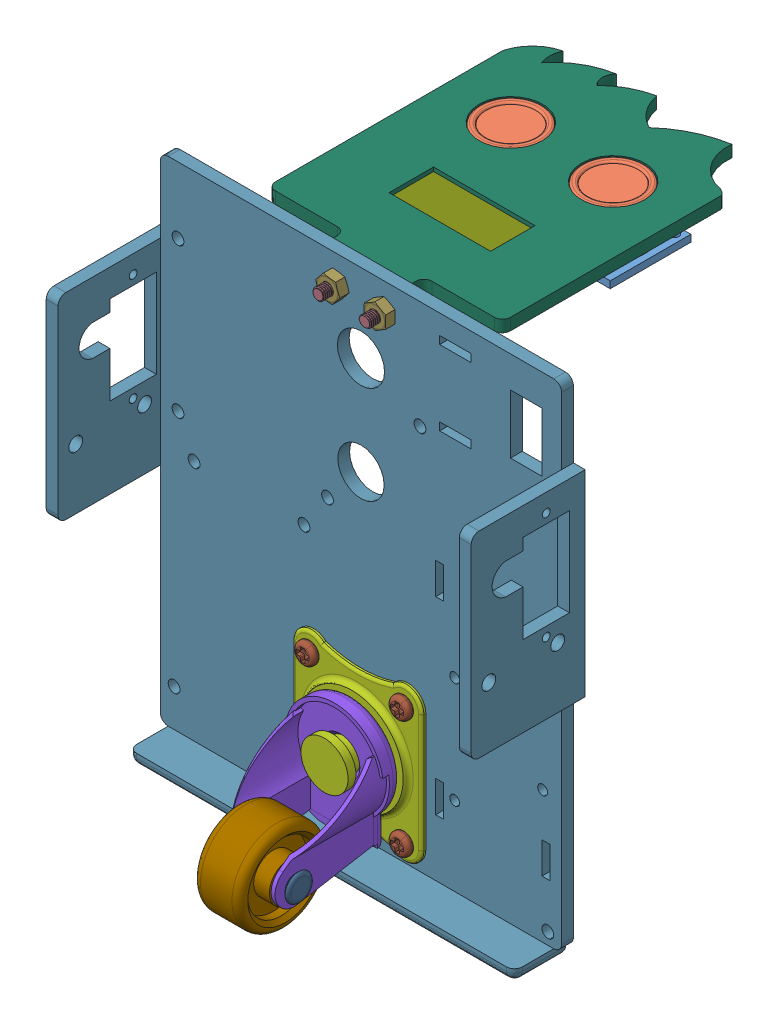
SolidWorks assembly DYOR_3D_OL, configuration Predeterminado. Lengths in mm.
Overall size (108 131.39 112.97).
53 component instances, 19 part files, 17 mates.
Components (placement in the parent):
- HC-SR04 Ping Sensor-1: HC-SR04 Ping Sensor [Default] at (9.5272 28.7888 -38.4611) x (0 0 -1) z (0 1 0) size (25.18 45 18.07)
  - PCB-1: PCB [Default] at origin size (20.5 45 1.75)
  - Transducer-1: Transducer [Default] at (0 -13 13.25) x (1 0 0) z (0 -1 0) size (15.88 12 15.88)
  - Transducer-2: Transducer [Default] at (0 13 13.25) x (1 0 0) z (0 -1 0) size (15.88 12 15.88)
  - 3 Pin Header 90 Degree-1: 3 Pin Header 90 Degree [Default] at (8.4275 0 -1.25) x (-1 0 0) z (0 -1 0) size (8 7.82 10)
  - 14 Pin SMT-1: 14 Pin SMT [Default] at (-0.35 -18.5 -0.85) x (0 -1 0) z (1 0 0) size (6 1.6 8.8)
  - 14 Pin SMT-2: 14 Pin SMT [Default] at (0 -0.3826 -0.85) x (1 0 0) z (0 1 0) size (6 1.6 8.8)
  - 14 Pin SMT-3: 14 Pin SMT [Default] at (0 17.5274 -0.85) x (1 0 0) z (0 1 0) size (6 1.6 8.8)
  - Cap1 SMT-1: Cap1 SMT [Default] at (-1.755 7.4774 -0.9689) x (0 1 0) z (-1 0 0) size (4.5 1.84 1.75)
  - Cap1 SMT-2: Cap1 SMT [Default] at (6.835 7.4774 -0.9689) x (0 1 0) z (-1 0 0) size (4.5 1.84 1.75)
  - Cap1 SMT-3: Cap1 SMT [Default] at (-6.835 7.4774 -0.9689) x (0 1 0) z (-1 0 0) size (4.5 1.84 1.75)
  - Cap1 SMT-4: Cap1 SMT [Default] at (4.295 7.4774 -0.9689) x (0 1 0) z (-1 0 0) size (4.5 1.84 1.75)
  - Cap1 SMT-5: Cap1 SMT [Default] at (1.755 7.4774 -0.9689) x (0 1 0) z (-1 0 0) size (4.5 1.84 1.75)
  - Cap1 SMT-6: Cap1 SMT [Default] at (-4.295 7.4774 -0.9689) x (0 1 0) z (-1 0 0) size (4.5 1.84 1.75)
  - HC-SR04 Crystal-1: HC-SR04 Crystal [Default] at (-8.3 0 1.75) x (0 -1 0) z (0 0 1) size (10 3.5 2.7)
- CA-1: CA [Predeterminado] at (-2.207 18.0036 0) size (33 45.94 43.2)
  - Caster Wheel-1: Caster Wheel [Default] at (57.6387 -78.841 57.7572) x (0 1 0) z (-1 0 0) size (45.94 37.59 33)
    - caster holder-1: caster holder [Default] at (-24.0751 44.7184 29.5137) x (1 0 0) z (0 0 -1) size (39 9.27 33)
    - holder-1: holder [Default] at (-1.5751 42.9484 46.0137) x (0 0 1) z (1 0 0) size (25 28.07 31.31)
    - caster wheel-1: caster wheel [Default] at (-15.6961 19.9484 46.0137) x (0.997275 0.073773 0) z (0 0 1) size (23 23 14)
    - Part4-1: Part4 [Default] at (-15.6961 19.9484 55.0137) x (-0.978448 0.206495 0) z (0 0 -1) size (7 7 20)
  - M3x6 Philips Screw-1: M3x6 Philips Screw [Predeterminado] at (23.625 -65.4161 13.5389) size (5.3 5.3 7.81)
  - M3x6 Philips Screw-2: M3x6 Philips Screw [Predeterminado] at (-0.375 -65.4161 13.5389) size (5.3 5.3 7.81)
  - M3x6 Philips Screw-3: M3x6 Philips Screw [Predeterminado] at (-0.375 -95.4161 13.5389) size (5.3 5.3 7.81)
  - M3x6 Philips Screw-4: M3x6 Philips Screw [Predeterminado] at (23.625 -95.4161 13.5389) size (5.3 5.3 7.81)
  - M3 Nut-1: M3 Nut [Predeterminado] at (23.625 -65.4161 11.0389) size (6.27 6.27 2.71)
  - M3 Nut-2: M3 Nut [Predeterminado] at (-0.375 -65.4161 11.0389) size (6.27 6.27 2.71)
  - M3 Nut-3: M3 Nut [Predeterminado] at (-0.375 -95.4161 11.0389) size (6.27 6.27 2.71)
  - M3 Nut-4: M3 Nut [Predeterminado] at (23.625 -95.4161 11.0389) size (6.27 6.27 2.71)
- M3x10 Philips Screw-2: M3x10 Philips Screw [Predeterminado] at (3.418 36.0388 7.5389) x (-0.665771 0.746156 0) z (0 0 -1) size (5.3 5.3 11.8)
- M3x10 Philips Screw-3: M3x10 Philips Screw [Predeterminado] at (15.418 36.0388 7.5389) x (0.006663 -0.999978 0) z (0 0 -1) size (5.3 5.3 11.8)
- M3 Nut-1: M3 Nut [Predeterminado] at (3.418 36.0388 16.5389) x (0.934299 0.356491 0) z (0 0 1) size (6.27 6.27 2.71)
- M3 Nut-2: M3 Nut [Predeterminado] at (15.418 36.0388 11.0389) x (-0.487763 -0.872976 0) z (0 0 -1) size (6.27 6.27 2.71)
- Base-1: Base [Predeterminado] at (60.418 -80.9125 12.5389) size (108 128.45 29)
- Front_OL-1: Front_OL [Predeterminado] at (-51.1718 39.5388 -46.4821) x (1 0 0) z (0 1 0) size (59.69 72.38 11)
- OLED_0.91_128x32-1: OLED_0.91_128x32 [Predeterminado] at (10.618 39.0288 -13.1552) x (1 0 0) z (0 1 0) size (38.3 12.1 11.46)
  - OLED_0.91_128x32.stp-1: OLED_0.91_128x32.stp [Predeterminado] at origin size (38.3 12.1 11.46)
    - OLED_0.91_128x32.stp-1: OLED_0.91_128x32.stp [Predeterminado] at origin size (38.3 12.1 2.57)
    - Pin Header 4 x 1 TH 2.54mm Pitch.stp-1: Pin Header 4 x 1 TH 2.54mm Pitch.stp [Predeterminado] at (-17.55 -3.81 -2.6) size (2.54 10.16 11.43)
    - RESC-0603.stp-1: RESC-0603.stp [Predeterminado] at (4.3 -5.3 0) x (1 0 0) z (0 0 -1) size (1.7 0.9 0.55)
    - RESC-0603.stp-2: RESC-0603.stp [Predeterminado] at (4.3 -3.8 0) x (1 0 0) z (0 0 -1) size (1.7 0.9 0.55)
    - RESC-0603.stp-3: RESC-0603.stp [Predeterminado] at (4.3 -2.3 0) x (1 0 0) z (0 0 -1) size (1.7 0.9 0.55)
    - RESC-0603.stp-4: RESC-0603.stp [Predeterminado] at (4.3 -0.8 0) x (1 0 0) z (0 0 -1) size (1.7 0.9 0.55)
    - RESC-0603.stp-5: RESC-0603.stp [Predeterminado] at (4.3 0.7 0) x (1 0 0) z (0 0 -1) size (1.7 0.9 0.55)
    - RESC-0603.stp-6: RESC-0603.stp [Predeterminado] at (4.3 2.2 0) x (1 0 0) z (0 0 -1) size (1.7 0.9 0.55)
    - RESC-0603.stp-7: RESC-0603.stp [Predeterminado] at (4.3 3.7 0) x (1 0 0) z (0 0 -1) size (1.7 0.9 0.55)
    - RESC-0603.stp-8: RESC-0603.stp [Predeterminado] at (4.3 5.2 0) x (1 0 0) z (0 0 -1) size (1.7 0.9 0.55)
    - RESC-0603.stp-9: RESC-0603.stp [Predeterminado] at (-1.4 -3.06 0) x (1 0 0) z (0 0 -1) size (1.7 0.9 0.55)
    - RESC-0603.stp-10: RESC-0603.stp [Predeterminado] at (-1.4 -1.56 0) x (1 0 0) z (0 0 -1) size (1.7 0.9 0.55)
    - RESC-0603.stp-11: RESC-0603.stp [Predeterminado] at (-1.4 -0.06 0) x (1 0 0) z (0 0 -1) size (1.7 0.9 0.55)
    - RESC-0603.stp-12: RESC-0603.stp [Predeterminado] at (-1.4 1.44 0) x (1 0 0) z (0 0 -1) size (1.7 0.9 0.55)
    - RESC-0603.stp-13: RESC-0603.stp [Predeterminado] at (-1.4 2.94 0) x (1 0 0) z (0 0 -1) size (1.7 0.9 0.55)
    - 2SD0601A.stp-1: 2SD0601A.stp [Predeterminado] at (-9.8 -1.3 -0.08) x (1 0 0) z (0 1 0) size (2.76 1.18 2.9)
Mates (geometry in assembly coordinates):
- Concéntrica15: concentric: circle of CA-1/Caster Wheel-1/caster holder-1; circle of Base-1
- Coincidente14: coincident: plane of CA-1/M3 Nut-4 through (21.418 -77.4125 9.5389) normal (0 0 1); plane of Base-1 through (-39.582 40.5388 9.5389) normal (0 0 -1)
- Concéntrica16: concentric: circle of CA-1/M3 Nut-1; circle of Base-1
- Concéntrica22: concentric: circle of M3x10 Philips Screw-2; circle of Base-1
- Concéntrica23: concentric: circle of M3 Nut-1; circle of Base-1
- Concéntrica24: concentric: circle of M3 Nut-2; circle of Base-1
- Coincidente31: coincident: plane of M3 Nut-1 through (3.418 36.0388 12.5389) normal (0 0 -1); plane of Base-1 through (-39.582 40.5388 12.5389) normal (0 0 1)
- Coincidente32: coincident: plane of M3 Nut-2 through (15.418 36.0388 12.5389) normal (0 0 -1); plane of Base-1 through (-39.582 40.5388 12.5389) normal (0 0 1)
- Coincidente33: coincident: plane of Base-1 through (-39.582 40.5388 9.5389) normal (0 0 -1); plane of Front_OL-1 through (-0.582 42.5388 9.5389) normal (0 0 1)
- Concéntrica25: concentric: circle of Base-1; circle of Front_OL-1
- Paralelo1: parallel: plane of Base-1 through (-39.582 42.5388 9.5389) normal (0 1 0); plane of Front_OL-1 through (-2.582 42.5388 8.5389) normal (0 1 0)
- Concéntrica26: concentric: circle of HC-SR04 Ping Sensor-1/Transducer-1; circle of Front_OL-1
- Coincidente35: coincident: plane of HC-SR04 Ping Sensor-1/Transducer-2 through (-3.4728 42.5388 -46.4011) normal (0 1 0); plane of Front_OL-1 through (-2.582 42.5388 8.5389) normal (0 1 0)
- Concéntrica27: concentric: circle of HC-SR04 Ping Sensor-1/Transducer-2; circle of Front_OL-1
- Coincidente36: coincident: plane of Front_OL-1 through (22.318 42.5388 -18.8052) normal (0 0 1); plane of OLED_0.91_128x32-1/OLED_0.91_128x32.stp-1/OLED_0.91_128x32.stp-1 through (22.318 41.4788 -18.8052) normal (0 0 -1)
- Distancia1: distance = 1 mm: plane of Front_OL-1 through (-2.582 42.5388 8.5389) normal (0 1 0); plane of OLED_0.91_128x32-1/OLED_0.91_128x32.stp-1/OLED_0.91_128x32.stp-1 through (9.418 41.5388 -13.1552) normal (0 1 0)
- Coincidente40: coincident: plane of Front_OL-1 through (-3.482 42.5388 -18.8052) normal (1 0 0); plane of OLED_0.91_128x32-1/OLED_0.91_128x32.stp-1/OLED_0.91_128x32.stp-1 through (-3.482 41.4788 -18.8052) normal (-1 0 0)
